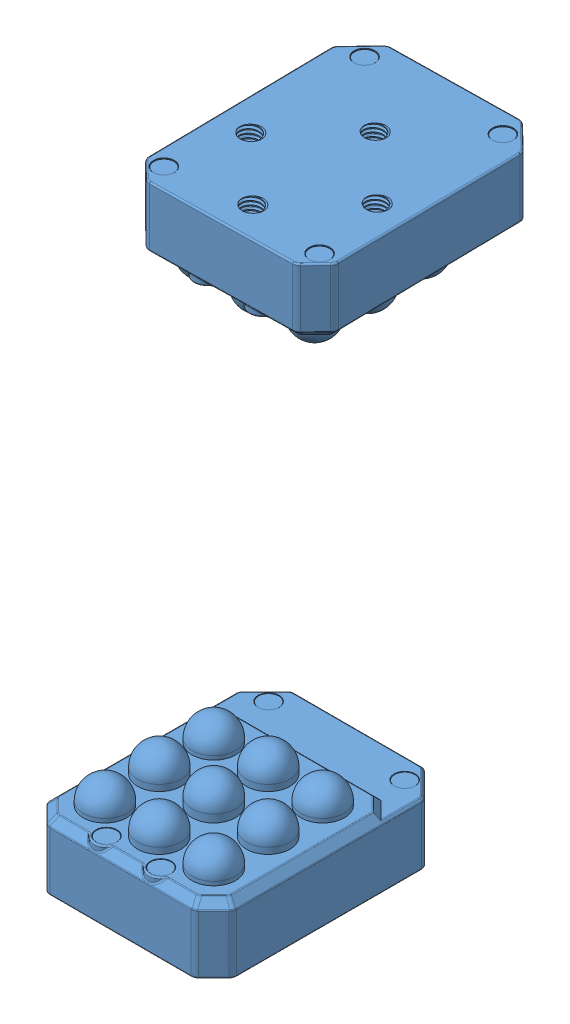
SolidWorks assembly peghole4, configuration Default. Lengths in mm.
Overall size (24.74 73.9 43.12).
4 component instances, 3 part files, 7 mates.
Components (placement in the parent):
- PTS_2.0.step-1: PTS_2.0.step [Default] at (-14.1008 11.3363 31.1385) size (24.01 12.45 30.73)
- cube peg-1: cube peg [默认] at (-12.6697 45.0983 -3.2702) x (0.999979 0 0.006511) z (-0.006511 0 0.999979) (suppressed, hidden)
- cubehole-1: cubehole [默认] at (-33.1261 51.4676 63.1708) x (0.999979 0 0.006511) z (-0.005548 0.523393 0.852073) (suppressed, hidden)
- PTS_2.0.step-3: PTS_2.0.step [Default] at (-13.5598 73.5363 18.9383) x (-0.999868 0 0.016262) z (0.016262 0 0.999868) size (24.01 12.45 30.73)
Mates (geometry in assembly coordinates):
- 平行6: parallel anti-aligned: plane of PTS_2.0.step-1 through (-14.1008 14.1363 27.8385) normal (0 1 0); plane of cube peg-1 through (-43.5792 17.4363 86.5304) normal (0 -1 0)
- 相切17: tangent anti-aligned: sphere of PTS_2.0.step-1; plane of cube peg-1 through (-43.5792 17.4363 86.5304) normal (0 -1 0)
- 平行7: parallel anti-aligned: plane of cube peg-1 through (-43.5792 67.4363 86.5304) normal (0 1 0); plane of PTS_2.0.step-3 through (-13.6135 70.7363 15.6387) normal (0 -1 0)
- 相切18: tangent anti-aligned: plane of cube peg-1 through (-43.5792 67.4363 86.5304) normal (0 1 0); unknown of PTS_2.0.step-3
- 重合10: coincident: line of cube peg-1; line of cubehole-1 through (6.6361 67.4363 53.6208) axis (-0.999979 0 -0.006511)
- 重合11: coincident anti-aligned: plane of cube peg-1 through (6.4197 67.4363 86.856) normal (0.999979 0 0.006511); plane of cubehole-1 through (6.3587 93.606 96.2245) normal (-0.999979 0 -0.006511)
- 重合12: coincident: line of cube peg-1 through (-43.5792 17.4363 86.5304) axis (0.999979 0 0.006511); plane of cubehole-1 through (-53.8445 42.4805 127.2367) normal (0.003408 0.852091 -0.523382)
